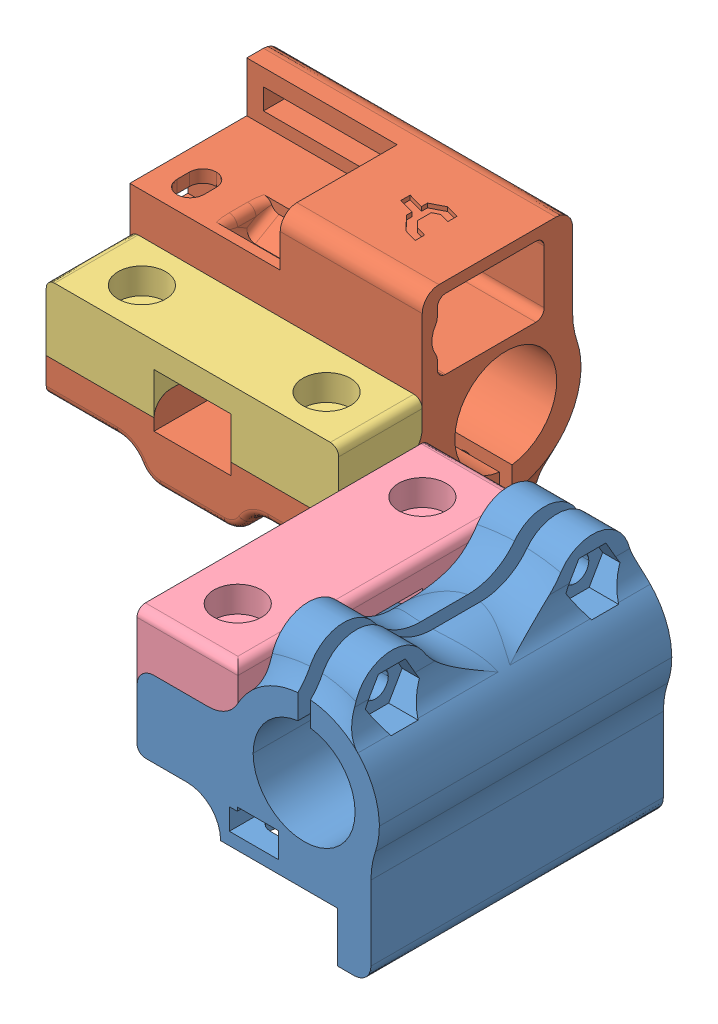
SolidWorks assembly Сборка1, configuration По умолчанию. Lengths in mm.
Overall size (91.06 45 80.19).
4 component instances, 4 part files, 16 mates.
Components (placement in the parent):
- Belt Tensioner 8mm X-1: Belt Tensioner 8mm X [По умолчанию] x (-1 0 0) z (0 0 1) size (31.48 30.5 35.02)
- Belt Tensioner 8mm Y-1: Belt Tensioner 8mm Y [По умолчанию] at (-44.5679 -18 -33.7021) x (0 0 1) z (-1 0 0) size (31.48 30.5 35.02)
- holder^Сборка1-1: holder^Сборка1 [По умолчанию] at (-79.5679 -18 -33.7021) x (0 0 1) z (-1 0 0) size (10 8 35) (virtual)
- holderX^Сборка1-1: holderX^Сборка1 [По умолчанию] at (0 0 35) x (-1 0 0) z (0 0 1) size (12.07 8 35) (virtual)
Mates (geometry in assembly coordinates):
- Параллельность1: parallel anti-aligned: plane of Belt Tensioner 8mm X-1 through (-18 -10.71 0) normal (0 0 -1); plane of Belt Tensioner 8mm Y-1 through (-79.5679 -3 -23.7021) normal (0 0 1)
- Параллельность2: parallel anti-aligned: plane of Belt Tensioner 8mm X-1 through (6 -17 35) normal (0 -1 0); plane of Belt Tensioner 8mm Y-1 through (-79.5679 -1 -39.7021) normal (0 1 0)
- Расстояние1: distance = 18 mm: cylinder of Belt Tensioner 8mm X-1 through (0 0 -0.2918) axis (0 0 1) radius 6.1; cylinder of Belt Tensioner 8mm Y-1 through (-44.2761 -18 -33.7021) axis (-1 0 0) radius 6.1
- На месте1: in place: plane of Belt Tensioner 8mm Y-1 through (-79.5679 -34 -23.4552) normal (-1 0 0); plane of ? through (-79.5679 0 0) normal (-1 0 0); moOrthogonalPlaneRef_w of Belt Tensioner 8mm Y-1 through (-79.5679 -34 -23.4552) normal (-1 0 0); plane of ? through (-79.5679 0 0) normal (0 1 0); plane of Belt Tensioner 8mm Y-1 through (-79.5679 -34 -23.4552) normal (-1 0 0); plane of ? through (-79.5679 0 0) normal (0 0 1); plane of Belt Tensioner 8mm Y-1 through (-79.5679 -34 -23.4552) normal (-1 0 0); unknown of holder^Сборка1-1
- Совпадение1: coincident aligned: plane of ?; plane of ?
- Совпадение2: coincident aligned: moOrthogonalPlaneRef_w of Belt Tensioner 8mm Y-1 through (-79.5679 -18 -33.7021) normal (0 1 0); plane of holder^Сборка1-1 through (-79.5679 -18 -33.7021) normal (0 1 0)
- Совпадение3: coincident anti-aligned: moOrthogonalPlaneRef_w of Belt Tensioner 8mm Y-1 through (-79.5679 -18 -33.7021) normal (0 0 -1); plane of holder^Сборка1-1 through (-79.5679 -18 -33.7021) normal (0 0 1)
- Концентричный3: concentric: cylinder of Belt Tensioner 8mm X-1 through (-14.3956 -10.85 28.55) axis (0 1 0) radius 1.5; cylinder of holder^Сборка1-2 through (-14.3956 29.4367 28.55) axis (0 -1 0) radius 1.5
- Концентричный4: concentric anti-aligned: cylinder of Belt Tensioner 8mm X-1 through (-14.3956 -10.85 6.45) axis (0 1 0) radius 1.5; cylinder of holder^Сборка1-2 through (-14.3956 12.4515 6.45) axis (0 -1 0) radius 1.5
- Совпадение9: coincident: plane of Belt Tensioner 8mm X-1 through (-20 0 0) normal (-1 0 0); plane of holder^Сборка1-3 through (-20 4.5512 46.6619) normal (-1 0 0)
- Параллельность6: parallel: plane of Belt Tensioner 8mm X-1 through (-56.1637 2.15 12.9) normal (0 1 0); plane of holder^Сборка1-3 through (-13 4.5512 46.6619) normal (0 -1 0)
- Совпадение11: coincident aligned: plane of Belt Tensioner 8mm X-1 through (-18 -10.71 35) normal (0 0 1); plane of holder^Сборка1-3 through (-10.247 -14.0249 35) normal (0 0 1)
- На месте2: in place: plane of Belt Tensioner 8mm X-1 through (-18 -10.71 35) normal (0 0 1); plane of ? through (0 0 35) normal (0 0 1); plane of Belt Tensioner 8mm X-1 through (-18 -10.71 35) normal (0 0 1); plane of ? through (0 0 35) normal (0 1 0); plane of Belt Tensioner 8mm X-1 through (-18 -10.71 35) normal (0 0 1); plane of ? through (0 0 35) normal (1 0 0); plane of Belt Tensioner 8mm X-1 through (-18 -10.71 35) normal (0 0 1); unknown of holderX^Сборка1-1
- Совпадение12: coincident aligned: plane of ?; plane of ?
- Совпадение13: coincident aligned: moOrthogonalPlaneRef_w of Belt Tensioner 8mm X-1 through (0 0 35) normal (0 -1 0); plane of Деталь2^Сборка1-1 through (0 0 35) normal (0 -1 0)
- Совпадение14: coincident anti-aligned: moOrthogonalPlaneRef_w of Belt Tensioner 8mm X-1 through (0 0 35) normal (1 0 0); plane of Деталь2^Сборка1-1 through (0 0 35) normal (-1 0 0)
